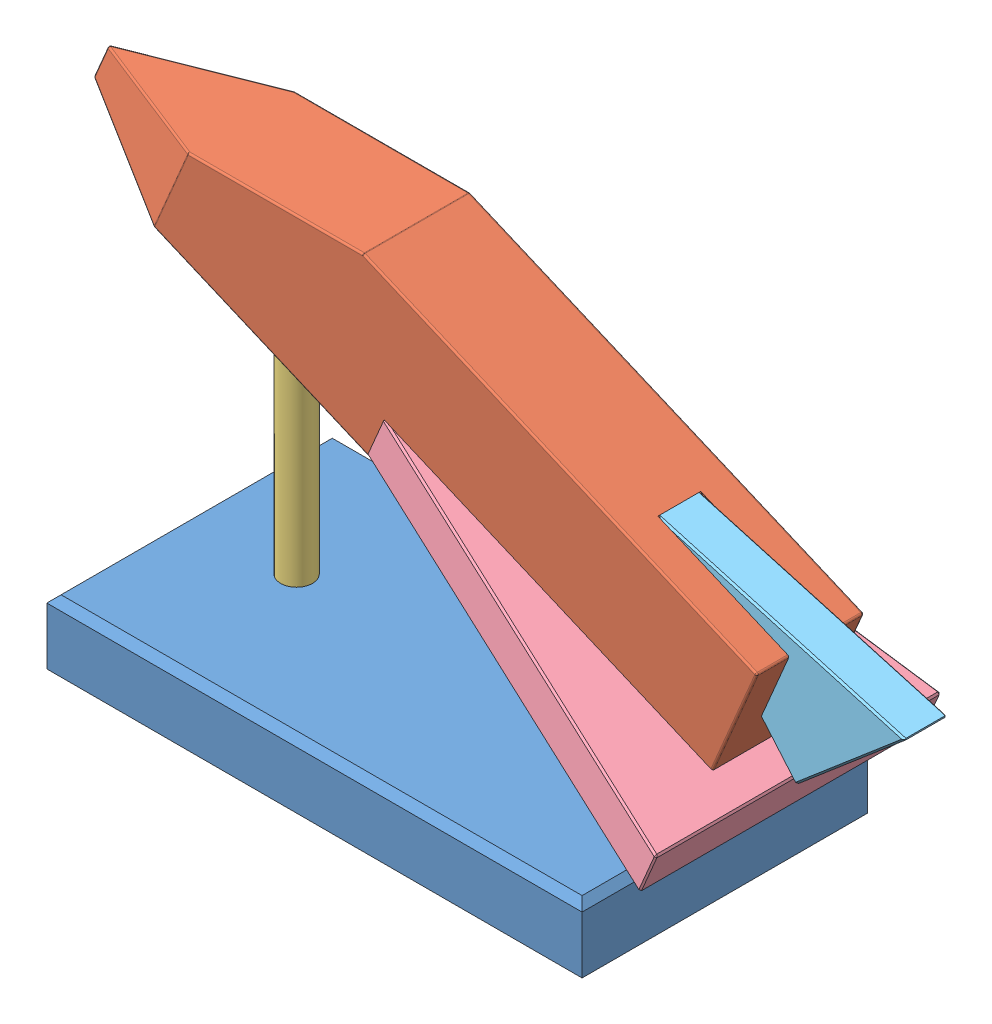
SolidWorks assembly Shuttle Assembly, configuration Default. Lengths in mm.
Overall size (232.95 150.99 80).
5 component instances, 5 part files, 10 mates.
Components (placement in the parent):
- Shutttle Base-2: Shutttle Base [Default] at (-1.1214 -7.9666 -1.0696) size (150 18 80)
- Shuttle Body-2: Shuttle Body [Default] at (-2.6948 83.9633 -1.0696) x (0.920331 -0.391141 0) z (0 0 1) size (199.23 44 30)
- Dowel-5: Dowel [Default] at (-46.1214 -7.9666 -1.0696) size (9 100 9)
- Shuttle Wing-2: Shuttle Wing [Default] at (89.9365 20.6905 -1.0696) x (0.920331 -0.391141 0) z (0 0 1) size (110 12 79.8)
- Shuttle Tail-2: Shuttle Tail [Default] at (61.1301 80.7421 -7.0696) x (0.648246 -0.761431 0) z (0 0 1) size (60 39.8 12)
Mates (geometry in assembly coordinates):
- Parallel2: parallel: plane of Shutttle Base-2 through (-76.1214 -7.9666 -41.0696) normal (0 -1 0); plane of assembly
- Coincident11: coincident: plane of Shutttle Base-2 through (-76.1214 -7.9666 -41.0696) normal (0 -1 0); plane of Dowel-5 through (-46.1214 -7.9666 -1.0696) normal (0 -1 0)
- Coincident12: coincident aligned: circle of Shutttle Base-2; circle of Dowel-5
- Coincident13: coincident aligned: circle of Shuttle Body-2; circle of Dowel-5
- Coincident14: coincident: plane of Shuttle Body-2 through (85.4269 35.6459 -16.0696) normal (-0.391141 -0.920331 0); plane of Shuttle Wing-2 through (-6.6062 74.76 -16.0696) normal (0.391141 0.920331 0)
- Coincident15: coincident: line of Shuttle Body-2 through (-11.2999 63.716 -15.5696) axis (0 0 1); line of Shuttle Wing-2 through (-11.2999 63.716 -15.5569) axis (0 0 1)
- Coincident16: coincident aligned: line of Shuttle Body-2 through (-6.6062 74.76 13.9304) axis (-0.391141 -0.920331 0); line of Shuttle Wing-2 through (-6.8018 74.2998 13.9304) axis (-0.391141 -0.920331 0)
- Coincident17: coincident: plane of Shuttle Body-2 through (61.1301 80.7421 4.9304) normal (0.761431 0.648246 0); plane of Shuttle Tail-2 through (61.1301 80.7421 4.9304) normal (-0.761431 -0.648246 0)
- Coincident18: coincident: line of Shuttle Body-2 through (61.1301 80.7421 4.9304) axis (0 0 -1); line of Shuttle Tail-2 through (61.1301 80.7421 4.4304) axis (0 0 -1)
- Coincident19: coincident anti-aligned: plane of Shuttle Body-2 through (97.9434 65.0965 4.9304) normal (0 0 -1); plane of Shuttle Tail-2 through (130.4821 60.9861 4.9304) normal (0 0 1)
